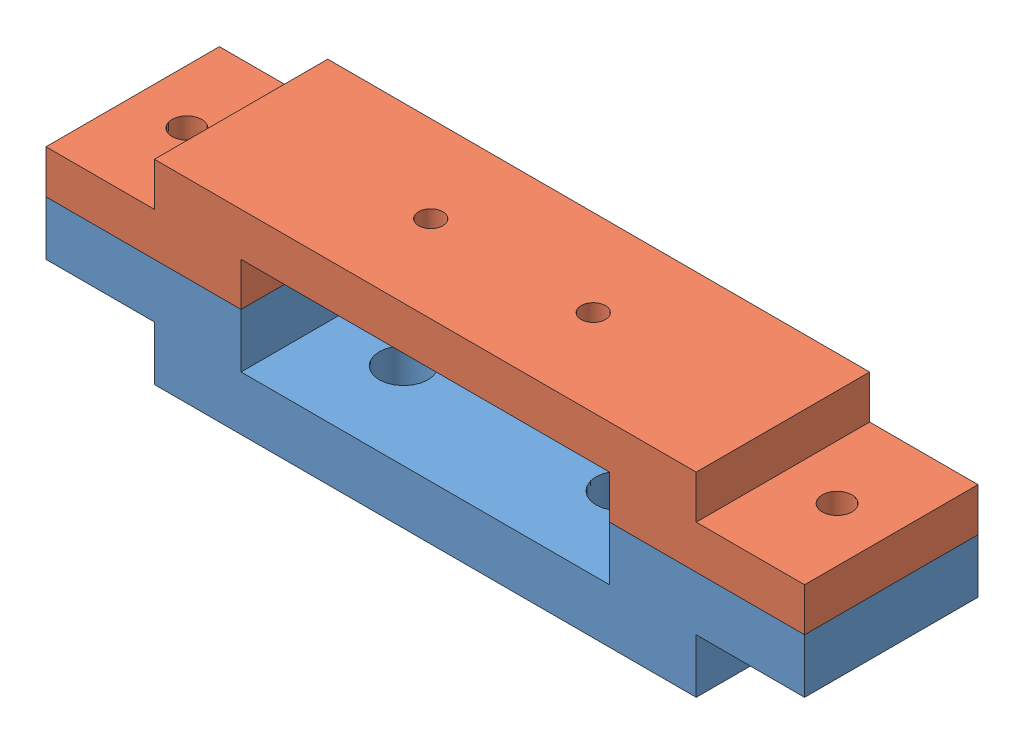
SolidWorks assembly adapter_assembly, configuration Standard. Lengths in mm.
Overall size (140 36 32).
2 component instances, 2 part files, 8 mates.
Components (placement in the parent):
- adapter_schlauch_typ_1-1: adapter_schlauch_typ_1 [Standard] at origin size (140 20 32)
- adapter_robot-1: adapter_robot [Standard] at (0 0 32) size (140 16 32)
Mates (geometry in assembly coordinates):
- Platziert1: in place: plane of adapter_schlauch_typ_1-1 through (0 0 0) normal (0 0 1); moOrthogonalPlaneRef_w of adapter_schlauch_typ_1-1 through (0 0 0) normal (0 1 0); plane of adapter_schlauch_typ_1-1 through (0 0 0) normal (1 0 0); unknown of adapter_schlauch_typ_1-1
- Deckungsgleich1: coincident aligned: 
- Deckungsgleich2: coincident aligned: plane of adapter_schlauch_typ_1-1 through (0 0 0) normal (0 1 0)
- Deckungsgleich3: coincident anti-aligned: plane of adapter_schlauch_typ_1-1 through (0 0 0) normal (1 0 0)
- Platziert2: in place: plane of adapter_schlauch_typ_1-1 through (0 0 32) normal (0 0 1); plane of adapter_robot-1 through (0 0 32) normal (0 0 1); plane of adapter_schlauch_typ_1-1 through (0 0 32) normal (0 0 1); plane of adapter_robot-1 through (0 0 32) normal (0 1 0); plane of adapter_schlauch_typ_1-1 through (0 0 32) normal (0 0 1); plane of adapter_robot-1 through (0 0 32) normal (1 0 0); plane of adapter_schlauch_typ_1-1 through (0 0 32) normal (0 0 1); unknown of adapter_robot-1
- Deckungsgleich4: coincident aligned: plane of ?; plane of ?
- Deckungsgleich5: coincident aligned: moOrthogonalPlaneRef_w of adapter_schlauch_typ_1-1 through (0 0 32) normal (0 1 0); plane of Teil3^adapter_schlauch_typ_1-1 through (0 0 32) normal (0 1 0)
- Deckungsgleich6: coincident anti-aligned: moOrthogonalPlaneRef_w of adapter_schlauch_typ_1-1 through (0 0 32) normal (-1 0 0); plane of Teil3^adapter_schlauch_typ_1-1 through (0 0 32) normal (1 0 0)
